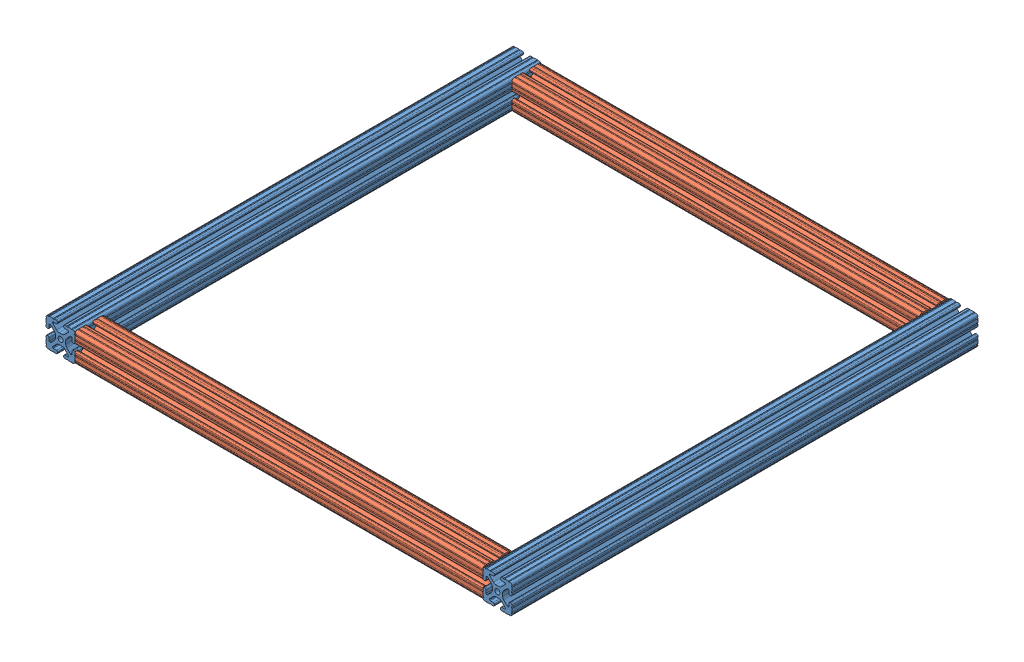
SolidWorks assembly Superstructure, configuration Default. Lengths in mm.
Overall size (609.6 38.1 609.6).
4 component instances, 2 part files, 9 mates.
Components (placement in the parent):
- T-Slot Top Long-1: T-Slot Top Long [47065T21] at (82.9387 391.4039 494.442) size (38.1 38.1 609.6)
- T-Slot Top Long-2: T-Slot Top Long [47065T21] at (654.4387 391.4039 494.442) size (38.1 38.1 609.6)
- T-Slot Top Short-1: T-Slot Top Short [47065T21] at (368.6887 391.4039 780.192) x (0 0 -1) z (1 0 0) size (38.1 38.1 533.4)
- T-Slot Top Short-2: T-Slot Top Short [47065T21] at (368.6887 391.4039 208.692) x (0 0 1) z (-1 0 0) size (38.1 38.1 533.4)
Mates (geometry in assembly coordinates):
- Coincident1: coincident: plane of T-Slot Top Long-1 through (101.9887 397.0215 799.242) normal (1 0 0); plane of T-Slot Top Short-1 through (101.9887 404.9563 789.5773) normal (-1 0 0)
- Coincident2: coincident: plane of T-Slot Top Long-1 through (73.5534 404.9563 799.242) normal (0 0 1); plane of T-Slot Top Short-1 through (635.3887 399.3802 799.242) normal (0 0 1)
- Coincident3: coincident aligned: plane of T-Slot Top Long-1 through (90.9129 410.4539 799.242) normal (0 1 0); plane of T-Slot Top Short-1 through (635.3887 410.4539 785.8096) normal (0 1 0)
- Coincident4: coincident: plane of T-Slot Top Long-2 through (635.3887 399.3802 799.242) normal (-1 0 0); plane of T-Slot Top Short-1 through (635.3887 404.9563 789.5773) normal (1 0 0)
- Coincident5: coincident: plane of T-Slot Top Long-2 through (645.0534 404.9563 799.242) normal (0 0 1); plane of T-Slot Top Short-1 through (635.3887 399.3802 799.242) normal (0 0 1)
- Coincident6: coincident aligned: plane of T-Slot Top Long-2 through (648.8211 410.4539 799.242) normal (0 1 0); plane of T-Slot Top Short-1 through (635.3887 410.4539 785.8096) normal (0 1 0)
- Coincident7: coincident: plane of T-Slot Top Long-1 through (101.9887 397.0215 799.242) normal (1 0 0); plane of T-Slot Top Short-2 through (101.9887 404.9563 199.3067) normal (-1 0 0)
- Coincident8: coincident: plane of T-Slot Top Long-1 through (90.9129 410.4539 799.242) normal (0 1 0); plane of T-Slot Top Short-2 through (101.9887 410.4539 203.0743) normal (0 1 0)
- Coincident9: coincident aligned: plane of T-Slot Top Long-1 through (73.5534 404.9563 189.642) normal (0 0 -1); plane of T-Slot Top Short-2 through (101.9887 385.7863 189.642) normal (0 0 -1)
